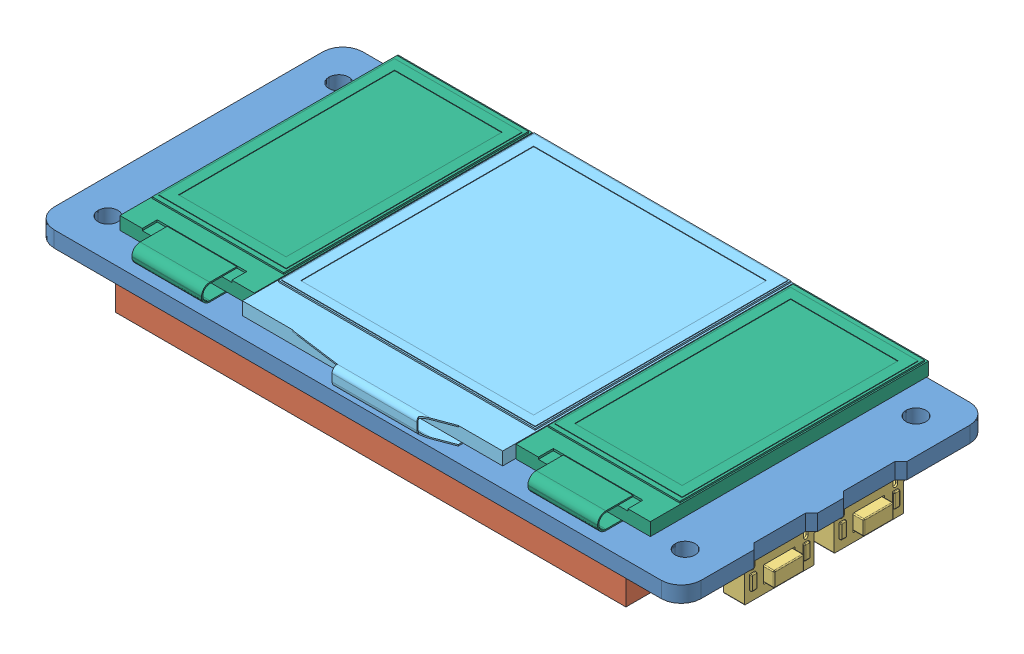
SolidWorks assembly zero-lcd-hat_a, configuration Default. Lengths in mm.
Overall size (65.35 7.4 31).
10 component instances, 6 part files, 0 mates.
Components (placement in the parent):
- zero-lcd-hat_a.stp-1: zero-lcd-hat_a.stp [Default] at origin size (65.35 7.4 31)
  - ZERO-LCD-HAT_A-PCBA_ASM.stp-1: ZERO-LCD-HAT_A-PCBA_ASM.stp [Default] at origin size (65.35 5.4 31)
    - ZERO-LCD-HAT_A-PCB.stp-1: ZERO-LCD-HAT_A-PCB.stp [Default] at origin size (65 1.6 31)
    - HEADER-SMD-F-2_54-2X20P-H3_5.stp-1: HEADER-SMD-F-2_54-2X20P-H3_5.stp [Default] at (0 -2.4 13.77) x (-1 0 0) z (0 0 1) size (51.3 3.61 6.61)
    - SWITCH-7X3_3X3_5.stp-1: SWITCH-7X3_3X3_5.stp [Default] at (31.65 -2.05 3.27) x (0 0 1) z (1 0 0) size (7.8 4.25 3.7)
    - SWITCH-7X3_3X3_5.stp-2: SWITCH-7X3_3X3_5.stp [Default] at (31.65 -2.05 -5.73) x (0 0 1) z (1 0 0) size (7.8 4.25 3.7)
    - 001.stp-1: 001.stp [Default] at origin size (46 1 12)
  - 1_3INCH-240X240-LCD.stp-1: 1_3INCH-240X240-LCD.stp [Default] at origin size (26.16 2.02 30.54)
  - 0_96INCH-80X160-LCD.stp-1: 0_96INCH-80X160-LCD.stp [Default] at (19.9 0 -0.48) size (13.5 2 30)
  - 0_96INCH-80X160-LCD.stp-2: 0_96INCH-80X160-LCD.stp [Default] at (-19.9 0 -0.48) size (13.5 2 30)
